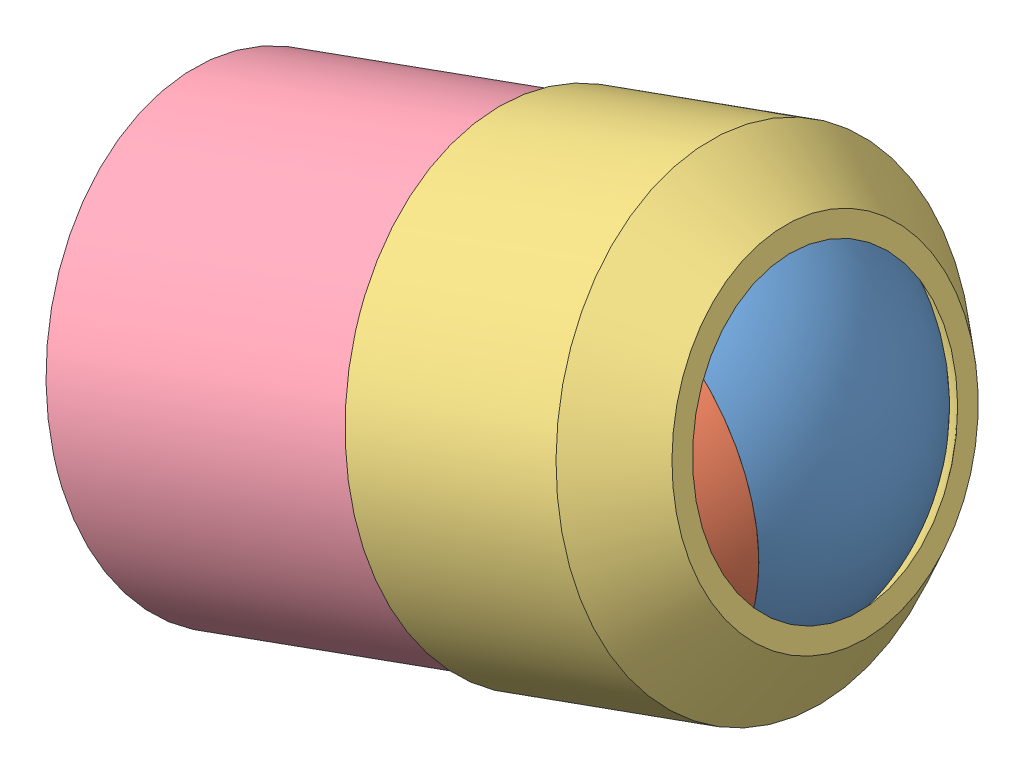
SolidWorks assembly Arm substitute assembly v2, configuration Default. Lengths in mm.
Overall size (120.04 114.26 108.98).
4 component instances, 4 part files, 5 mates.
Components (placement in the parent):
- partie émant v2-1: partie émant v2 [Default] at (3.813 46.4178 58.7892) size (70 70 50)
- partie émant v2 p2-1: partie émant v2 p2 [Default] at (38.9019 11.4179 58.7892) x (-0.00254 0.999997 0) z (0 0 1) size (63.25 63.25 19.1)
- Arm substitute 1 v2-1: Arm substitute 1 v2 [Default] at (64.5568 54.2252 56.4861) x (-0.120378 0.624551 0.771651) z (-0.953472 -0.289164 0.085298) size (75 75 45)
- Arm substitute 2 v2-1: Arm substitute 2 v2 [Default] at (-26.9765 26.4654 64.6747) x (0.090983 -0.006249 0.995833) z (0.953472 0.289164 -0.085298) size (72 72 64)
Mates (geometry in assembly coordinates):
- Coincident1: coincident anti-aligned: plane of partie émant v2-1 through (3.813 46.4178 73.7892) normal (0 0 1); plane of partie émant v2 p2-1 through (44.6283 42.5213 73.7892) normal (0 0 -1)
- Concentric1: concentric aligned: cylinder of partie émant v2 p2-1 through (38.813 46.4178 73.7892) axis (0 0 1) radius 7.9; cylinder of émant collé sur le telephone v2-1 through (38.813 46.4178 81.5158) axis (0 0 1) radius 7.4
- Concentric4: concentric: sphere of partie émant v2-1; sphere of Arm substitute 2 v2-1
- Concentric7: concentric aligned: cylinder of Arm substitute 1 v2-1 through (38.813 46.4178 58.7892) axis (0.058744 0.051236 -0.996957) radius 36.5; cylinder of Arm substitute 2 v2-1 through (38.5193 46.1616 63.774) axis (0.058744 0.051236 -0.996957) radius 36
- Concentric8: concentric: sphere of partie émant v2 p2-1; sphere of Arm substitute 1 v2-1
